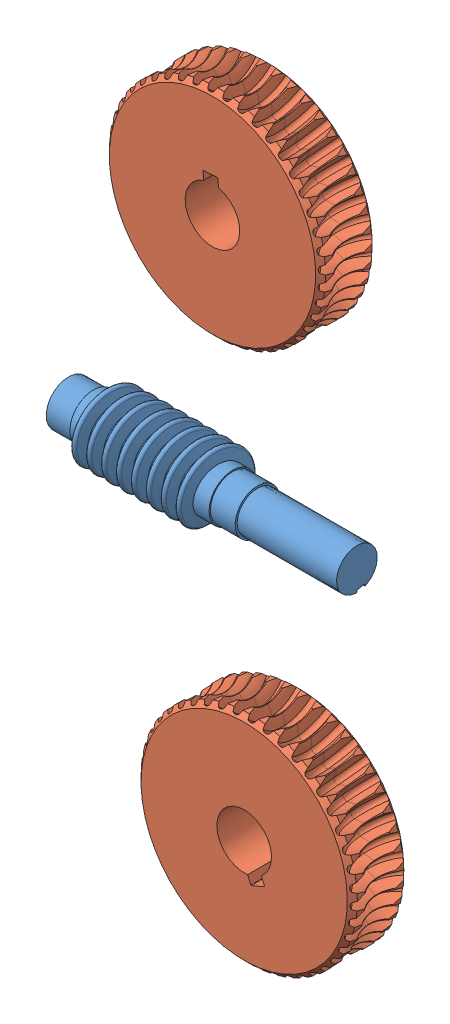
SolidWorks assembly warm gear, configuration Default. Lengths in mm.
Overall size (96.21 159.06 20.63).
3 component instances, 2 part files, 8 mates.
Components (placement in the parent):
- Screw-1: Screw [Default] at (-28.7256 41.5828 -2.4548) x (1 0 0) z (0 0.208785 -0.977962) size (83.73 14.51 18)
- worm gear-1: worm gear [Default] at (0.0096 -0.0226 0) x (-0.920182 -0.39149 0) z (0 0 1) size (44.95 44.95 11.35)
- worm gear-2: worm gear [Default] at (-6.3795 105.8917 0) x (0.998399 0.056556 0) z (0 0 1) size (44.95 44.95 11.35)
Mates (geometry in assembly coordinates):
- Coincident1: coincident: plane of worm gear-1 through (0.0096 -0.0226 0) normal (0 0 1); plane of assembly through (0 0 0) normal (0 0 1)
- Concentric1: concentric: cylinder of worm gear-1 through (0 0 5.675) axis (0 0 -1) radius 5.5; point of assembly
- Coincident3: coincident: axis of Screw-1 through (7 53.08 0) axis (1 0 0); plane of assembly
- Distance1: distance = 41 mm: plane of Screw-1 through (-41 53.08 0) normal (-1 0 0); plane of assembly through (0 0 0) normal (1 0 0)
- Distance2: distance = 53.08 mm: axis of Screw-1 through (-41 53.08 0) axis (1 0 0); plane of assembly
- GearMate1: gear = 11 : 16.5 mm: cylinder of Screw-1 through (42.7256 53.0861 0.0016) axis (1 0 0) radius 4.1; cylinder of worm gear-1 through (-0.0096 0.0226 5.675) axis (0 0 -1) radius 5.5
- GearMate2: gear = 11 : 16.5 mm: cylinder of Screw-1 through (42.7256 53.0861 0.0016) axis (1 0 0) radius 4.1; cylinder of worm gear-2 through (-6.3781 105.8672 5.675) axis (0 0 -1) radius 5.5
- Coincident8: coincident: plane of worm gear-1 through (0 0 -5.675) normal (0 0 -1); plane of worm gear-2 through (-6.3781 105.8672 -5.675) normal (0 0 -1)
